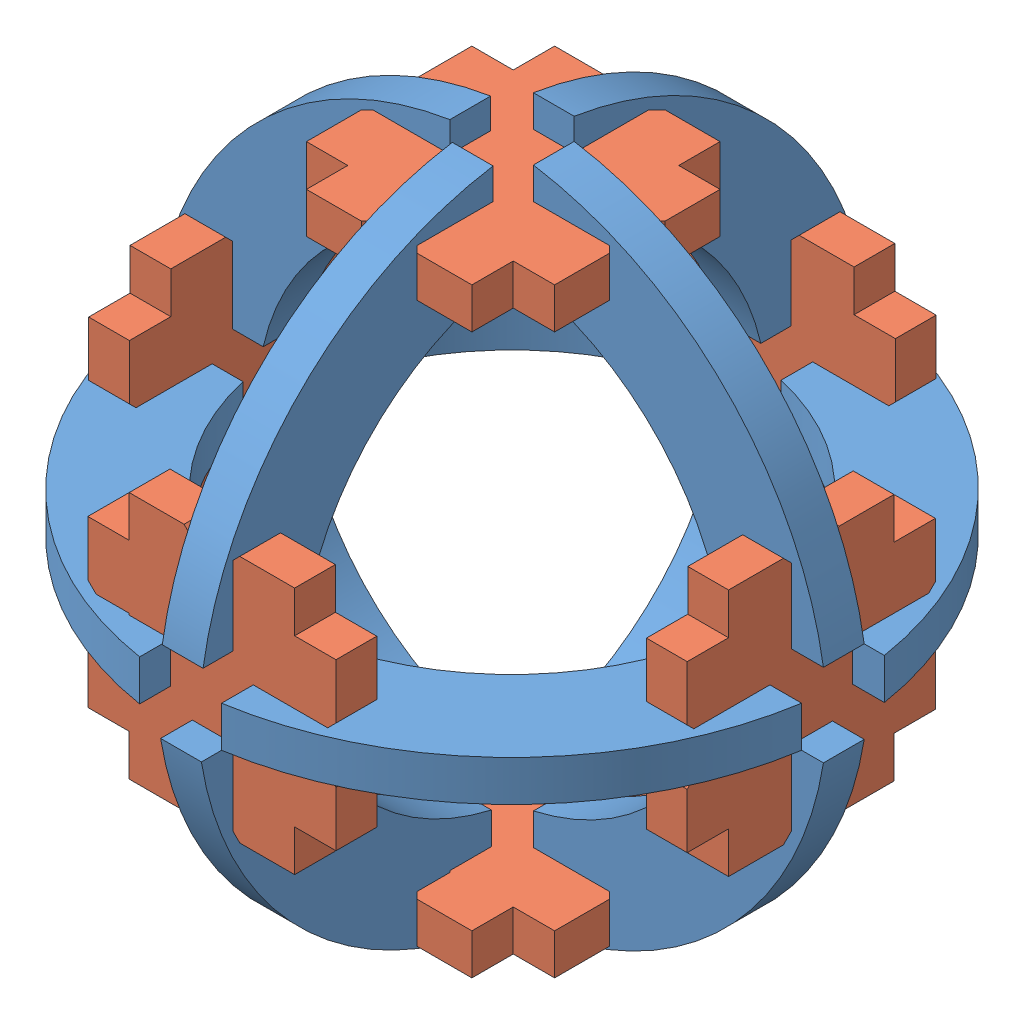
SolidWorks assembly sphere_assembly, configuration Default. Lengths in mm.
Overall size (101.76 102.01 102.01).
20 component instances, 2 part files, 27 mates.
Components (placement in the parent):
- half_dome-1: half_dome [Default] at (-8.3806 5.0603 -16.2814) size (44.53 101.76 101.76)
  - slot_2-1: slot_2 [Default] at (-30.949 10.2199 14.3089) size (44.53 6.26 44.53)
  - slot_2-3: slot_2 [Default] at (-30.949 6.8734 23.6624) x (1 0 0) z (0 1 0) size (44.53 6.26 44.53)
  - slot_2-4: slot_2 [Default] at (-30.949 19.5734 17.4013) x (1 0 0) z (0 -1 0) size (44.53 6.26 44.53)
  - slot_2-5: slot_2 [Default] at (-30.949 16.481 27.0089) x (1 0 0) z (0 0 -1) size (44.53 6.26 44.53)
  - connector-1: connector [Default] at (-11.9145 13.2234 28.4443) x (0 -1 0) z (0 0 1) size (38.1 6.26 38.1)
- half_dome-2: half_dome [Default] at (-111.7026 4.8063 24.9094) x (-1 0 0) z (0 0 -1) size (44.53 101.76 101.76)
  - slot_2-1: slot_2 [Default] at (-30.949 10.2199 14.3089) size (44.53 6.26 44.53)
  - slot_2-3: slot_2 [Default] at (-30.949 6.8734 23.6624) x (1 0 0) z (0 1 0) size (44.53 6.26 44.53)
  - slot_2-4: slot_2 [Default] at (-30.949 19.5734 17.4013) x (1 0 0) z (0 -1 0) size (44.53 6.26 44.53)
  - slot_2-5: slot_2 [Default] at (-30.949 16.481 27.0089) x (1 0 0) z (0 0 -1) size (44.53 6.26 44.53)
  - connector-1: connector [Default] at (-11.9145 13.2234 28.4443) x (0 -1 0) z (0 0 1) size (38.1 6.26 38.1)
- connector-1: connector [Default] at (-60.0416 58.0302 11.9089) size (38.1 6.26 38.1)
- connector-2: connector [Default] at (-60.0416 10.7523 44.124) x (1 0 0) z (0 -1 0) size (38.1 6.26 38.1)
- connector-5: connector [Default] at (-60.0416 -27.8509 11.9089) size (38.1 6.26 38.1)
- connector-6: connector [Default] at (-60.0416 26.0692 -35.4961) x (1 0 0) z (0 1 0) size (38.1 6.26 38.1)
- slot_2-1: slot_2 [Default] at (-63.0451 -2.4283 -2.0995) x (0 -1 0) z (0 0 1) size (44.53 6.26 44.53)
- slot_2-2: slot_2 [Default] at (-63.0451 12.1877 25.0895) x (0 0 1) z (0 1 0) size (44.53 6.26 44.53)
- slot_2-3: slot_2 [Default] at (-56.784 24.5067 24.8355) x (0 0 1) z (0 -1 0) size (44.53 6.26 44.53)
- slot_2-4: slot_2 [Default] at (-63.2991 24.6337 -16.5886) x (0 0 -1) z (0 -1 0) size (44.53 6.26 44.53)
Mates (geometry in assembly coordinates):
- Coincident6: coincident anti-aligned: plane of half_dome-1/slot_2-4 through (-47.3416 58.1572 7.381) normal (-1 0 0); plane of connector-1 through (-47.3416 64.2913 7.127) normal (1 0 0)
- Coincident7: coincident anti-aligned: plane of half_dome-1/slot_2-4 through (-47.3416 64.2913 7.381) normal (0 -1 0); plane of connector-1 through (-63.0451 64.2913 23.1735) normal (0 1 0)
- Coincident8: coincident anti-aligned: plane of half_dome-1/slot_2-4 through (-62.1807 16.1446 1.1199) normal (0 0 -1); plane of connector-1 through (-47.3416 64.2913 1.1199) normal (0 0 1)
- Coincident9: coincident anti-aligned: plane of half_dome-1/slot_2-5 through (-62.1807 21.5413 2.2383) normal (0 1 0); plane of connector-2 through (-47.3416 21.5413 50.3851) normal (0 -1 0)
- Coincident10: coincident anti-aligned: plane of half_dome-1/slot_2-5 through (-47.3416 15.2802 44.251) normal (-1 0 0); plane of connector-2 through (-47.3416 15.5342 50.3851) normal (1 0 0)
- Coincident11: coincident anti-aligned: plane of half_dome-1/slot_2-5 through (-47.3416 15.2802 50.3851) normal (0 0 -1); plane of connector-2 through (-63.0451 -0.5123 50.3851) normal (0 0 1)
- Coincident12: coincident anti-aligned: plane of half_dome-1/slot_2-3 through (-47.3416 -21.5898 1.1199) normal (-1 0 0); plane of connector-5 through (-47.3416 -21.5898 7.127) normal (1 0 0)
- Coincident13: coincident anti-aligned: plane of half_dome-1/slot_2-3 through (-47.3416 -21.5898 1.1199) normal (0 -1 0); plane of connector-5 through (-63.0451 -21.5898 23.1735) normal (0 1 0)
- Coincident14: coincident anti-aligned: plane of half_dome-1/slot_2-3 through (-62.1807 20.4229 1.1199) normal (0 0 -1); plane of connector-5 through (-47.3416 -21.5898 1.1199) normal (0 0 1)
- Coincident15: coincident anti-aligned: plane of half_dome-1/slot_2-1 through (-47.3416 21.5413 -35.4961) normal (-1 0 0); plane of connector-6 through (-47.3416 21.2873 -41.7572) normal (1 0 0)
- Coincident16: coincident anti-aligned: plane of half_dome-1/slot_2-1 through (-47.3416 21.5413 -35.4961) normal (0 0 -1); plane of connector-6 through (-63.0451 37.3337 -35.4961) normal (0 0 1)
- Coincident17: coincident anti-aligned: plane of half_dome-1/slot_2-1 through (-62.1807 15.2802 6.5166) normal (0 -1 0); plane of connector-6 through (-47.3416 15.2802 -41.7572) normal (0 1 0)
- Coincident18: coincident anti-aligned: plane of half_dome-2/slot_2-5 through (-72.7416 15.0262 -35.6231) normal (1 0 0); plane of connector-6 through (-72.7416 21.2873 -41.7572) normal (-1 0 0)
- Coincident19: coincident: plane of half_dome-2/slot_2-5 through (-57.9024 21.2873 6.3896) normal (0 1 0); moEndPointRef_w of connector-6
- Coincident20: coincident anti-aligned: plane of half_dome-2/slot_2-5 through (-72.7416 15.0262 -41.7572) normal (0 0 1); plane of connector-6 through (-63.0451 37.3337 -41.7572) normal (0 0 -1)
- Coincident21: coincident anti-aligned: plane of connector-6 through (-63.0451 5.5837 -41.7572) normal (0 -1 0); plane of slot_2-1 through (-56.784 5.5837 -35.6231) normal (0 1 0)
- Coincident22: coincident anti-aligned: plane of connector-6 through (-63.0451 -0.7663 -41.7572) normal (1 0 0); plane of slot_2-1 through (-63.0451 20.4229 6.3896) normal (-1 0 0)
- Coincident23: coincident anti-aligned: plane of connector-6 through (-63.0451 37.3337 -41.7572) normal (0 0 -1); plane of slot_2-1 through (-56.784 5.5837 -41.7572) normal (0 0 1)
- Coincident24: coincident anti-aligned: plane of connector-2 through (-63.0451 5.8377 50.3851) normal (0 -1 0); plane of slot_2-2 through (-56.784 5.8377 44.251) normal (0 1 0)
- Coincident25: coincident anti-aligned: plane of connector-2 through (-63.0451 -0.5123 50.3851) normal (1 0 0); plane of slot_2-2 through (-63.0451 20.6769 2.2383) normal (-1 0 0)
- Coincident26: coincident anti-aligned: plane of connector-2 through (-63.0451 -0.5123 50.3851) normal (0 0 1); plane of slot_2-2 through (-56.784 12.1877 50.3851) normal (0 0 -1)
- Coincident27: coincident anti-aligned: plane of connector-1 through (-63.0451 64.2913 16.8235) normal (0 0 1); plane of slot_2-3 through (-63.0451 58.0302 16.8235) normal (0 0 -1)
- Coincident28: coincident anti-aligned: plane of connector-1 through (-63.0451 64.2913 23.1735) normal (1 0 0); plane of slot_2-3 through (-63.0451 16.0176 1.9843) normal (-1 0 0)
- Coincident30: coincident anti-aligned: plane of connector-1 through (-63.0451 58.0302 23.1735) normal (0 -1 0); plane of slot_2-3 through (-63.0451 58.0302 16.8235) normal (0 1 0)
- Coincident31: coincident anti-aligned: plane of connector-1 through (-63.0451 64.2913 -8.5765) normal (0 0 -1); plane of slot_2-4 through (-57.038 58.1572 -8.5765) normal (0 0 1)
- Coincident32: coincident anti-aligned: plane of connector-1 through (-57.038 64.2913 -14.9265) normal (-1 0 0); plane of slot_2-4 through (-57.038 16.1446 6.2626) normal (1 0 0)
- Coincident33: coincident anti-aligned: plane of connector-1 through (-63.0451 64.2913 23.1735) normal (0 1 0); plane of slot_2-4 through (-57.038 64.2913 -8.5765) normal (0 -1 0)
